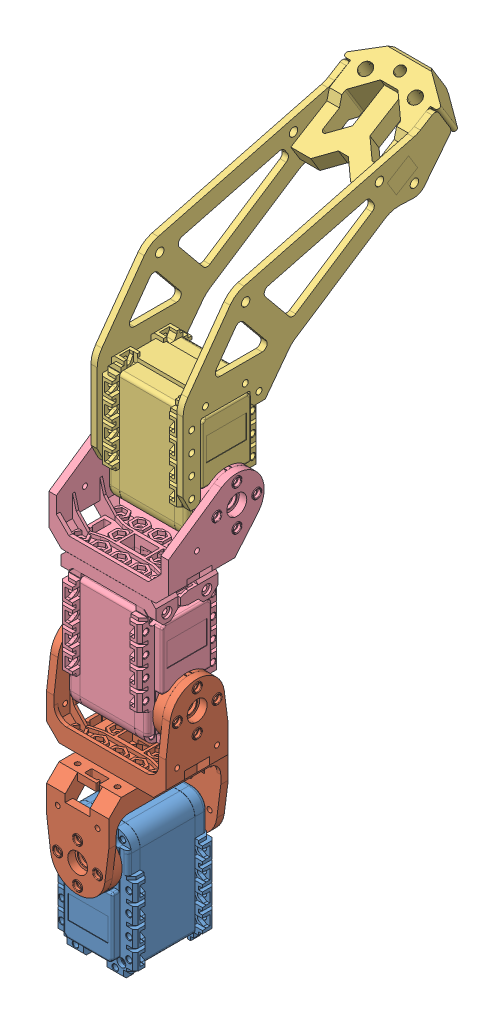
SolidWorks assembly Left_Leg_join_with_Servo, configuration Default. Lengths in mm.
Overall size (49.4 253.44 138.92).
4 component instances, 4 part files, 9 mates.
Components (placement in the parent):
- ServoBody-1: ServoBody [Default] at (1.7715 35.525 50.0961) size (32 50.04 38.67)
- Coxa_left-2: Coxa_left [Default] at (47.5771 50.0986 54.2581) x (0 0 1) z (-1 0 0) size (48.5 75 48.5)
- Tibia_left-1: Tibia_left [Default] at (-41.8386 194.8219 31.577) x (0 0 1) z (1 0 0) size (116.62 108.98 38.67)
- Femur_left-1: Femur_left [Default] at (40.1398 114.3313 34.2621) x (0 0 1) z (-1 0 0) size (42.04 87.04 48.5)
Mates (geometry in assembly coordinates):
- Concentric1: concentric anti-aligned: cylinder of ServoBody-1 through (1.7715 35.525 63.4961) axis (0 0 1) radius 4.6; cone of Coxa_left-2 through (1.7715 35.525 66.3561) axis (0 0 -1)
- Coincident1: coincident anti-aligned: plane of ServoBody-1 through (-3.0125 30.741 63.4961) normal (0 0 1); plane of Coxa_left-2 through (-2.4019 31.3559 63.4961) normal (0 0 -1)
- Parallel1: parallel aligned: plane of ServoBody-1 through (14.7715 0.735 35.0161) normal (1 0 0); plane of Coxa_left-2 through (14.2723 62.025 25.1961) normal (1 0 0)
- Concentric2: concentric anti-aligned: cone of Coxa_left-2 through (18.9312 88.525 49.1964) axis (-1 0 0); cylinder of Femur_left-1 through (16.0712 88.525 49.1964) axis (1 0 0) radius 4.6
- Coincident3: coincident anti-aligned: plane of Coxa_left-2 through (16.0712 92.6941 45.023) normal (-1 0 0); plane of Femur_left-1 through (16.0712 93.309 44.4124) normal (1 0 0)
- Parallel2: parallel anti-aligned: plane of Coxa_left-2 through (-14.2288 69.025 61.6972) normal (0 1 0); plane of Femur_left-1 through (-12.4168 77.025 56.4764) normal (0 -1 0)
- Concentric3: concentric anti-aligned: cylinder of Tibia_left-1 through (16.9715 153.025 34.1538) axis (1 0 0) radius 4.6; cone of Femur_left-1 through (19.8315 153.025 34.1538) axis (-1 0 0)
- Coincident5: coincident anti-aligned: plane of Tibia_left-1 through (16.9715 157.809 29.3698) normal (1 0 0); plane of Femur_left-1 through (16.9715 157.1941 29.9804) normal (-1 0 0)
- Parallel3: parallel anti-aligned: plane of Tibia_left-1 through (-11.5165 141.525 41.4338) normal (0 -1 0); plane of Femur_left-1 through (-13.3285 136.025 64.1538) normal (0 1 0)
